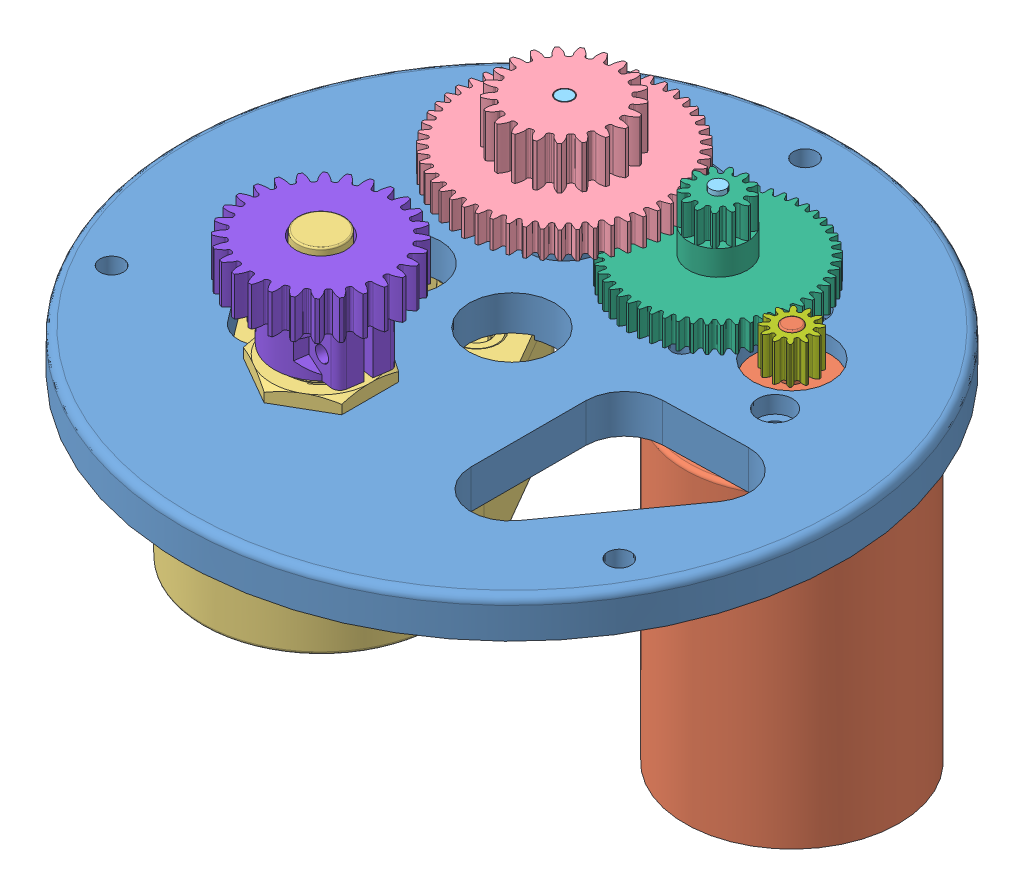
SolidWorks assembly motor_encoder_mount, configuration Default. Lengths in mm.
Overall size (85 60.72 85).
9 component instances, 8 part files, 22 mates.
Components (placement in the parent):
- gear_plate-1: gear_plate [Default] at (29.6826 29.2508 68.6333) size (85 11 85)
- motor-1: motor [Default] at (51.2418 -10.7492 54.1006) x (-0.558952 0 -0.8292) z (0.8292 0 -0.558952) size (27.6 49 27.6)
- S5-X-236-X-S-B-1: S5-X-236-X-S-B [Default] at (22.1087 29.7508 85.6937) x (0.866025 0 -0.5) z (0 -1 0) size (31.05 47.11 36.8)
- gear2-1: gear2 [Default] at (22.1295 40.2508 54.3019) x (-0.767256 0 -0.641341) z (0 1 0) size (27 27 9)
- rod1-1: rod1 [Default] at (38.0033 30.2508 50.3849) x (0.295414 0 -0.955369) z (0.955369 0 0.295414) size (2 15 2)
- rod1-2: rod1 [Default] at (22.1295 34.2508 54.3019) x (-0.913157 0 0.407607) z (-0.407607 0 -0.913157) size (2 15 2)
- gear1-1: gear1 [Default] at (38.0033 34.2508 50.3849) x (-0.806349 0 -0.59144) z (0 1 0) size (22.68 22.68 10.3)
- gear0-2: gear0 [Default] at (51.2418 38.0508 54.1006) x (-0.207042 0 -0.978332) z (0 -1 0) size (6.16 6.16 4.8)
- gear3 v2-1: gear3 v2 [Default] at (22.1087 47.2692 85.6937) x (0.989255 0 0.146198) z (0 -1 0) size (20 20 12)
Mates (geometry in assembly coordinates):
- Concentric13: concentric anti-aligned: cylinder of gear_plate-1 through (22.1087 34.2508 85.6937) axis (0 -1 0) radius 5; cylinder of S5-X-236-X-S-B-1 through (22.1087 17.6604 85.6937) axis (0 1 0) radius 2.9972
- Concentric16: concentric anti-aligned: cylinder of gear_plate-1 through (51.2418 24.2508 54.1006) axis (0 1 0) radius 5.05; cylinder of motor-1 through (51.2418 32.2508 54.1006) axis (0 -1 0) radius 5
- Concentric17: concentric anti-aligned: circle of gear_plate-1; cylinder of motor-1 through (42.745 32.2508 59.8281) axis (0 -1 0) radius 1.225
- Concentric18: concentric aligned: cylinder of gear_plate-1 through (46.7702 24.2508 47.467) axis (0 1 0) radius 1.2; cylinder of motor-1 through (46.7702 26.2508 47.467) axis (0 1 0) radius 1
- Coincident20: coincident anti-aligned: plane of gear_plate-1 through (29.6826 29.2508 68.6333) normal (0 -1 0); plane of motor-1 through (51.2418 29.2508 54.1006) normal (0 1 0)
- Parallel2: parallel aligned: cylinder of gear_plate-1 through (29.6826 34.2508 68.6333) axis (0 -1 0) radius 42.5; cone of S5-X-236-X-S-B-1 through (18.0642 27.8458 60.4005) axis (0 -1 0)
- Coincident22: coincident anti-aligned: plane of gear_plate-1 through (22.0087 29.7508 85.5205) normal (0 -1 0); plane of S5-X-236-X-S-B-1 through (22.1087 29.7508 85.6937) normal (0 1 0)
- Coincident23: coincident anti-aligned: plane of gear_plate-1 through (22.1295 40.2508 54.3019) normal (0 1 0); plane of gear2-1 through (22.1295 40.2508 54.3019) normal (0 -1 0)
- Concentric22: concentric anti-aligned: circle of gear_plate-1; cylinder of rod1-1 through (38.0033 45.2508 50.3849) axis (0 -1 0) radius 1
- Coincident25: coincident anti-aligned: plane of gear_plate-1 through (29.6826 34.2508 68.6333) normal (0 1 0); plane of rod1-2 through (22.1295 34.2508 54.3019) normal (0 -1 0)
- Coincident26: coincident aligned: plane of gear_plate-1 through (38.0033 30.2508 50.3849) normal (0 1 0); circle of rod1-1
- Coincident28: coincident anti-aligned: plane of gear_plate-1 through (29.6826 34.2508 68.6333) normal (0 1 0); plane of gear1-1 through (38.0033 34.2508 50.3849) normal (0 -1 0)
- Distance1: distance = 1 mm anti-aligned: plane of gear0-2 through (48.4506 33.2508 53.345) normal (0 -1 0); plane of motor-1 through (51.2418 32.2508 54.1006) normal (0 1 0)
- GearMate2: gear = 52 : 12 mm: line of gear0-2 through (51.2418 33.2508 54.1006) axis (0 1 0); line of gear1-1 through (38.0033 44.6508 50.3849) axis (0 -1 0)
- Concentric27: concentric anti-aligned: cylinder of motor-1 through (51.2418 38.2508 54.1006) axis (0 -1 0) radius 1.25; cylinder of gear0-2 through (51.2418 33.2508 54.1006) axis (0 1 0) radius 1
- GearMate3: gear = 13 : 52 mm: line of gear2-1 through (22.1295 49.2508 54.3019) axis (0 -1 0); line of gear1-1 through (38.0033 40.7508 50.3849) axis (0 -1 0)
- Concentric28: concentric anti-aligned: cylinder of rod1-1 through (38.0033 45.2508 50.3849) axis (0 -1 0) radius 1; cylinder of gear1-1 through (38.0033 44.6508 50.3849) axis (0 1 0) radius 1
- Concentric29: concentric anti-aligned: cylinder of gear2-1 through (22.1295 52.2508 54.3019) axis (0 1 0) radius 1.1; cylinder of rod1-2 through (22.1295 49.2508 54.3019) axis (0 -1 0) radius 1
- Concentric30: concentric anti-aligned: circle of gear_plate-1; circle of gear2-1
- Parallel4: parallel aligned: line of gear_plate-1 through (-3.0261 29.2508 63.659) axis (0.866025 0 -0.5); line of S5-X-236-X-S-B-1 through (1.0798 29.7508 61.3692) axis (0.866025 0 -0.5)
- Concentric31: concentric aligned: cylinder of S5-X-236-X-S-B-1 through (22.1087 17.6604 85.6937) axis (0 1 0) radius 2.9972; cylinder of gear3 v2-1 through (22.1087 34.2692 85.6937) axis (0 1 0) radius 3.25
- Coincident29: coincident anti-aligned: plane of S5-X-236-X-S-B-1 through (22.1087 37.2692 85.6937) normal (0 1 0); plane of gear3 v2-1 through (22.1087 37.2692 85.6937) normal (0 -1 0)
